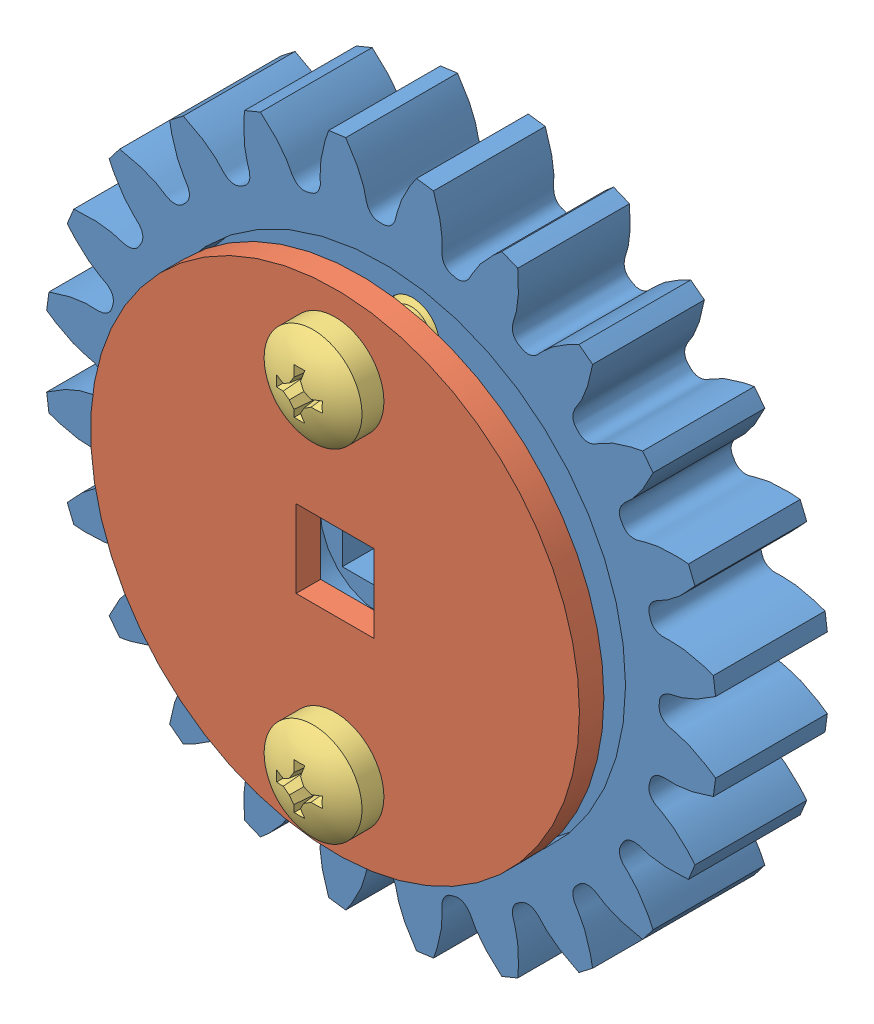
SolidWorks assembly reinforced 24T spur gear, configuration Default. Lengths in mm.
Overall size (27.69 27.69 8.92).
4 component instances, 3 part files, 8 mates.
Components (placement in the parent):
- Modified 24T gear-1: Modified 24T gear [24 teeth] at (10.9575 19.9925 17.007) size (27.69 27.69 6.35)
- double plate 24T gear-1: double plate 24T gear [Default] at (10.96 19.99 21.182) size (20 20 1)
- Tapping screw DIN 7049-ST2.2x6.5-C-H-S-1: Tapping screw DIN 7049-ST2.2x6.5-C-H-S [Tapping screw DIN 7049-ST2.2x6.5-C-H-S] at (10.96 12.99 21.182) x (0 0 -1) z (1 0 0) size (8.07 4 4)
- Tapping screw DIN 7049-ST2.2x6.5-C-H-S-2: Tapping screw DIN 7049-ST2.2x6.5-C-H-S [Tapping screw DIN 7049-ST2.2x6.5-C-H-S] at (10.96 26.99 21.182) x (0 0 -1) z (1 0 0) size (8.07 4 4)
Mates (geometry in assembly coordinates):
- Coincident1: coincident anti-aligned: plane of Modified 24T gear-1 through (10.9575 19.9925 20.182) normal (0 0 1); plane of double plate 24T gear-1 through (10.96 19.99 20.182) normal (0 0 -1)
- Parallel1: parallel anti-aligned: line of Modified 24T gear-1 through (12.545 21.58 19.293) axis (0 -1 0); line of double plate 24T gear-1 through (12.55 18.4 20.182) axis (0 1 0)
- Coincident4: coincident: line of Modified 24T gear-1 through (9.37 21.58 19.293) axis (1 0 0); plane of double plate 24T gear-1 through (12.55 21.58 11.182) normal (0 -1 0)
- Coincident5: coincident: plane of Modified 24T gear-1 through (9.37 21.58 14.721) normal (1 0 0); line of double plate 24T gear-1 through (9.37 21.58 21.182) axis (0 -1 0)
- Concentric1: concentric aligned: cylinder of double plate 24T gear-1 through (10.96 12.99 20.182) axis (0 0 1) radius 1.1; cylinder of Self tapping screw-1 through (10.96 12.99 21.182) axis (0 0 1) radius 1.1
- Coincident6: coincident anti-aligned: plane of double plate 24T gear-1 through (10.96 19.99 21.182) normal (0 0 1); plane of Self tapping screw-1 through (10.96 14.09 21.182) normal (0 0 -1)
- Concentric21: concentric aligned: cylinder of double plate 24T gear-1 through (10.96 26.99 20.182) axis (0 0 1) radius 1.1; cylinder of Self tapping screw-2 through (10.96 26.99 21.182) axis (0 0 1) radius 1.1
- Coincident71: coincident anti-aligned: plane of double plate 24T gear-1 through (10.96 19.99 21.182) normal (0 0 1); plane of Self tapping screw-2 through (10.96 28.09 21.182) normal (0 0 -1)
